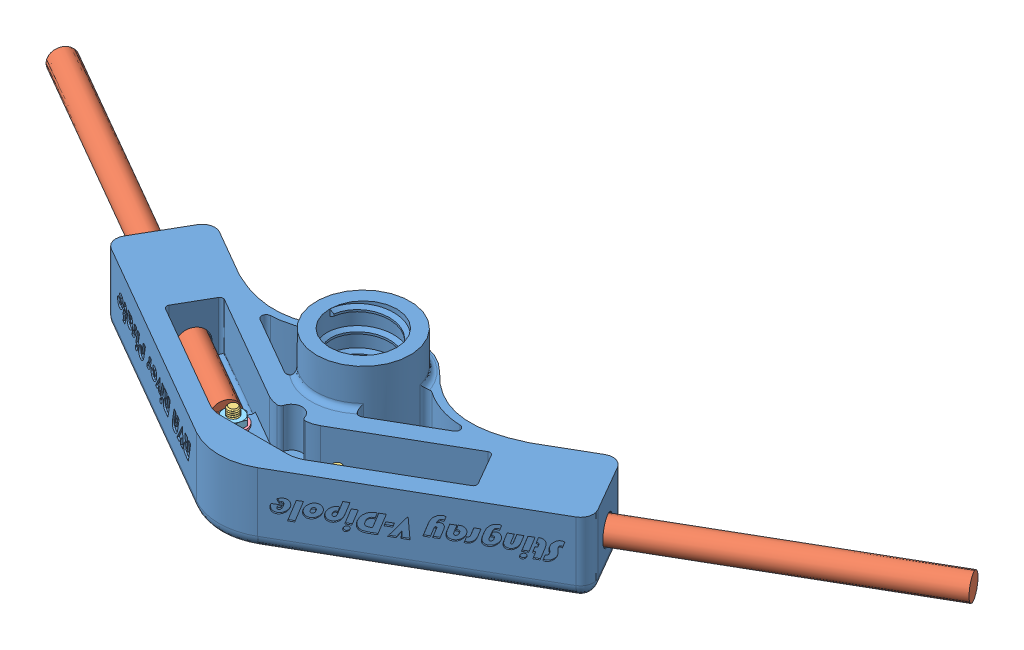
SolidWorks assembly AntennaAssembly, configuration Default. Lengths in mm.
Overall size (256.36 33.29 131.1).
11 component instances, 5 part files, 22 mates.
Components (placement in the parent):
- V-DipoleMount-1: V-DipoleMount [Default] at origin size (133.87 31.64 125)
- TelescopicAntenna-1: TelescopicAntenna [Default] at (18.7754 0 -10.84) x (0.5 0 0.866025) z (0 1 0) size (6.79 132.35 6.79)
- TelescopicAntenna-2: TelescopicAntenna [Default] at (-18.7754 0 -10.84) x (-0.5 0 0.866025) z (0 -1 0) size (6.79 132.35 6.79)
- 92095A184_BUTTON HEAD HEX DRIVE SCREW-1: 92095A184_BUTTON HEAD HEX DRIVE SCREW [92095A184] at (14.428 -12.25 -8.33) x (0.728313 0 0.685244) z (0 -1 0) size (5.7 5.7 17.83)
- 92095A184_BUTTON HEAD HEX DRIVE SCREW-2: 92095A184_BUTTON HEAD HEX DRIVE SCREW [92095A184] at (-14.428 -12.25 -8.33) x (0.47453 0 0.88024) z (0 -1 0) size (5.7 5.7 17.83)
- 93475A210_TYPE 18-8 STAINLESS STEEL FLAT WASHER-1: 93475A210_TYPE 18-8 STAINLESS STEEL FLAT WASHER [93475A210] at (14.428 1.385 -8.33) x (0.971825 0 -0.235704) z (0 -1 0) size (7 7 0.6)
- 93475A210_TYPE 18-8 STAINLESS STEEL FLAT WASHER-2: 93475A210_TYPE 18-8 STAINLESS STEEL FLAT WASHER [93475A210] at (-14.428 1.385 -8.33) x (0.889649 0 -0.456645) z (0 -1 0) size (7 7 0.6)
- 90695A033_CLASS 04 STEEL THIN HEX NUT - DIN 439B-1: 90695A033_CLASS 04 STEEL THIN HEX NUT - DIN 439B [90695A033] at (14.428 2.285 -8.33) x (0.75445 0 0.656358) z (-0.656358 0 0.75445) size (5.5 2.19 6.35)
- 90695A033_CLASS 04 STEEL THIN HEX NUT - DIN 439B-2: 90695A033_CLASS 04 STEEL THIN HEX NUT - DIN 439B [90695A033] at (-14.428 2.285 -8.33) x (0.970411 0 0.241457) z (-0.241457 0 0.970411) size (5.5 2.19 6.35)
- 93475A210_TYPE 18-8 STAINLESS STEEL FLAT WASHER-3: 93475A210_TYPE 18-8 STAINLESS STEEL FLAT WASHER [93475A210] at (-14.428 -10.6 -8.33) x (1 0 0) z (0 1 0) size (7 7 0.6)
- 93475A210_TYPE 18-8 STAINLESS STEEL FLAT WASHER-4: 93475A210_TYPE 18-8 STAINLESS STEEL FLAT WASHER [93475A210] at (14.428 -10.6 -8.33) x (1 0 0) z (0 1 0) size (7 7 0.6)
Mates (geometry in assembly coordinates):
- Concentric2: concentric anti-aligned: cylinder of V-DipoleMount-1 through (-40.4261 0 -23.34) axis (-0.866025 0 -0.5) radius 3.745; cylinder of TelescopicAntenna-2 through (-126.483 0 -73.025) axis (0.866025 0 0.5) radius 3.395
- Concentric3: concentric anti-aligned: cylinder of V-DipoleMount-1 through (40.4261 0 -23.34) axis (0.866025 0 -0.5) radius 3.745; cylinder of TelescopicAntenna-1 through (126.483 0 -73.025) axis (-0.866025 0 0.5) radius 3.395
- Coincident2: coincident anti-aligned: plane of V-DipoleMount-1 through (-15.7754 -39.6423 -16.0362) normal (-0.866025 0 -0.5); plane of TelescopicAntenna-2 through (-18.7754 0 -10.84) normal (0.866025 0 0.5)
- Parallel1: parallel aligned: plane of V-DipoleMount-1 through (0 -1.04 0) normal (0 1 0); plane of TelescopicAntenna-2 through (-11.8645 0.785 -6.85) normal (0 1 0)
- Coincident4: coincident anti-aligned: plane of V-DipoleMount-1 through (15.7754 -39.6423 -16.0362) normal (0.866025 0 -0.5); plane of TelescopicAntenna-1 through (18.7754 0 -10.84) normal (-0.866025 0 0.5)
- Parallel2: parallel aligned: plane of V-DipoleMount-1 through (0 -1.04 0) normal (0 1 0); plane of TelescopicAntenna-1 through (11.8645 0.785 -6.85) normal (0 1 0)
- Concentric4: concentric anti-aligned: cylinder of V-DipoleMount-1 through (14.428 -10 -8.33) axis (0 1 0) radius 1.625; circle of 92095A184_BUTTON HEAD HEX DRIVE SCREW-1
- Concentric5: concentric anti-aligned: cylinder of V-DipoleMount-1 through (-14.428 -10 -8.33) axis (0 1 0) radius 1.625; circle of 92095A184_BUTTON HEAD HEX DRIVE SCREW-2
- Concentric8: concentric anti-aligned: circle of 92095A184_BUTTON HEAD HEX DRIVE SCREW-2; cylinder of 93475A210_TYPE 18-8 STAINLESS STEEL FLAT WASHER-2 through (-14.428 0.785 -8.33) axis (0 1 0) radius 1.6
- Coincident8: coincident anti-aligned: plane of TelescopicAntenna-2 through (-11.8645 0.785 -6.85) normal (0 1 0); plane of 93475A210_TYPE 18-8 STAINLESS STEEL FLAT WASHER-2 through (-14.428 0.785 -8.33) normal (0 -1 0)
- Concentric10: concentric anti-aligned: circle of 92095A184_BUTTON HEAD HEX DRIVE SCREW-1; cylinder of 93475A210_TYPE 18-8 STAINLESS STEEL FLAT WASHER-1 through (14.428 0.785 -8.33) axis (0 1 0) radius 1.6
- Coincident9: coincident anti-aligned: plane of TelescopicAntenna-1 through (11.8645 0.785 -6.85) normal (0 1 0); plane of 93475A210_TYPE 18-8 STAINLESS STEEL FLAT WASHER-1 through (14.428 0.785 -8.33) normal (0 -1 0)
- Concentric11: concentric anti-aligned: circle of 93475A210_TYPE 18-8 STAINLESS STEEL FLAT WASHER-1; circle of 90695A033_CLASS 04 STEEL THIN HEX NUT - DIN 439B-1
- Coincident10: coincident anti-aligned: plane of 93475A210_TYPE 18-8 STAINLESS STEEL FLAT WASHER-1 through (14.428 1.385 -8.33) normal (0 1 0); plane of 90695A033_CLASS 04 STEEL THIN HEX NUT - DIN 439B-1 through (13.3954 1.385 -11.3328) normal (0 -1 0)
- Concentric12: concentric anti-aligned: circle of 93475A210_TYPE 18-8 STAINLESS STEEL FLAT WASHER-2; circle of 90695A033_CLASS 04 STEEL THIN HEX NUT - DIN 439B-2
- Coincident11: coincident anti-aligned: plane of 93475A210_TYPE 18-8 STAINLESS STEEL FLAT WASHER-2 through (-14.428 1.385 -8.33) normal (0 1 0); plane of 90695A033_CLASS 04 STEEL THIN HEX NUT - DIN 439B-2 through (-16.7132 1.385 -10.5347) normal (0 -1 0)
- Concentric13: concentric anti-aligned: circle of 92095A184_BUTTON HEAD HEX DRIVE SCREW-1; circle of 93475A210_TYPE 18-8 STAINLESS STEEL FLAT WASHER-4
- Coincident12: coincident anti-aligned: plane of 92095A184_BUTTON HEAD HEX DRIVE SCREW-1 through (16.3809 -10.6 -10.4057) normal (0 1 0); plane of 93475A210_TYPE 18-8 STAINLESS STEEL FLAT WASHER-4 through (14.428 -10.6 -8.33) normal (0 -1 0)
- Concentric14: concentric anti-aligned: circle of 92095A184_BUTTON HEAD HEX DRIVE SCREW-2; circle of 93475A210_TYPE 18-8 STAINLESS STEEL FLAT WASHER-3
- Coincident13: coincident anti-aligned: plane of 92095A184_BUTTON HEAD HEX DRIVE SCREW-2 through (-11.9193 -10.6 -9.6824) normal (0 1 0); plane of 93475A210_TYPE 18-8 STAINLESS STEEL FLAT WASHER-3 through (-14.428 -10.6 -8.33) normal (0 -1 0)
- Coincident14: coincident anti-aligned: plane of V-DipoleMount-1 through (0 -10 0) normal (0 -1 0); plane of 93475A210_TYPE 18-8 STAINLESS STEEL FLAT WASHER-3 through (-14.428 -10 -8.33) normal (0 1 0)
- Coincident15: coincident anti-aligned: plane of V-DipoleMount-1 through (0 -10 0) normal (0 -1 0); plane of 93475A210_TYPE 18-8 STAINLESS STEEL FLAT WASHER-4 through (14.428 -10 -8.33) normal (0 1 0)
